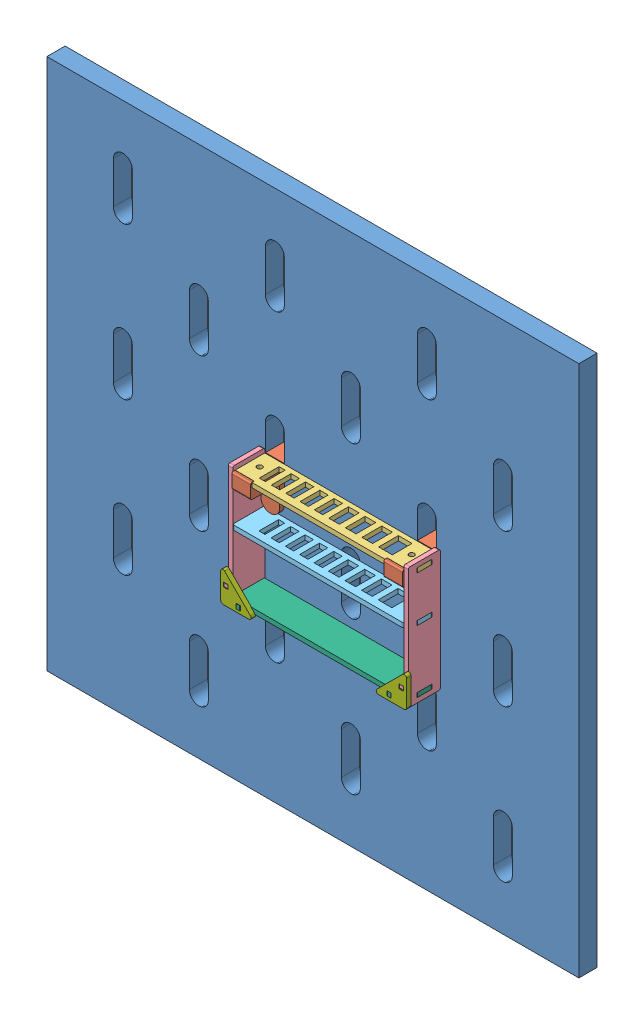
SolidWorks assembly 0 Органайзер пинцеты, configuration По умолчанию. Lengths in mm.
Overall size (350 350 46.14).
10 component instances, 7 part files, 25 mates.
Components (placement in the parent):
- 1 Стенка-1: 1 Стенка [По умолчанию] at origin size (350 350 12)
- 2 Кронштейн Пинцеты-1: 2 Кронштейн Пинцеты [По умолчанию] at (43.8 136.25 12) size (12.4 30 37.2)
- 2 Кронштейн Пинцеты-2: 2 Кронштейн Пинцеты [По умолчанию] at (143.8 136.25 12) size (12.4 30 37.2)
- 3 Полка верхняя Пинцеты-1: 3 Полка верхняя Пинцеты [По умолчанию] at (100.05 143.25 12.45) size (121.08 3 42.89)
- 4 Стенка пинцеты-1: 4 Стенка пинцеты [По умолчанию] at (40.8 109.175 22.95) size (3 80 23.85)
- 5 Полка средняя пинцеты-1: 5 Полка средняя пинцеты [По умолчанию] at (100.05 113.25 22.3) size (118.5 3 33.29)
- 4 Стенка пинцеты-2: 4 Стенка пинцеты [По умолчанию] at (156.3 109.175 22.95) size (3 80 23.85)
- 6 Полка нижняя пинцеты-1: 6 Полка нижняя пинцеты [По умолчанию] at (100.05 72.25 12.7) size (118.5 3 45.89)
- 7 уголок-1: 7 уголок [По умолчанию] at (161.3 70.25 33.7) size (22.07 22.07 3)
- 7 уголок-2: 7 уголок [По умолчанию] at (38.8 70.25 36.45) x (-1 0 0) z (0 0 -1) size (22.07 22.07 3)
Mates (geometry in assembly coordinates):
- Концентричный1: concentric aligned: cylinder of 2 Кронштейн Пинцеты-1 through (50.05 143.25 22.05) axis (0 1 0) radius 1.7; cylinder of 3 Полка верхняя Пинцеты-1 through (50.05 146.25 22.05) axis (0 1 0) radius 1.7
- Концентричный2: concentric aligned: cylinder of 2 Кронштейн Пинцеты-2 through (150.05 143.25 22.05) axis (0 1 0) radius 1.7; cylinder of 3 Полка верхняя Пинцеты-1 through (150.05 146.25 22.05) axis (0 1 0) radius 1.7
- Совпадение1: coincident anti-aligned: plane of 2 Кронштейн Пинцеты-2 through (156.2 143.25 12) normal (0 1 0); plane of 3 Полка верхняя Пинцеты-1 through (100.05 143.25 12.45) normal (0 -1 0)
- Совпадение2: coincident anti-aligned: plane of 2 Кронштейн Пинцеты-1 through (56.2 143.25 12) normal (0 1 0); plane of 3 Полка верхняя Пинцеты-1 through (100.05 143.25 12.45) normal (0 -1 0)
- Совпадение3: coincident anti-aligned: plane of 3 Полка верхняя Пинцеты-1 through (100.05 143.25 12.45) normal (0 -1 0); plane of 4 Стенка пинцеты-1 through (43.8 143.25 27.95) normal (0 1 0)
- Совпадение4: coincident anti-aligned: plane of 3 Полка верхняя Пинцеты-1 through (100.05 143.25 12.45) normal (0 -1 0); plane of 4 Стенка пинцеты-2 through (159.3 143.25 27.95) normal (0 1 0)
- Совпадение5: coincident anti-aligned: plane of 3 Полка верхняя Пинцеты-1 through (100.05 146.25 17.95) normal (0 0 -1); plane of 4 Стенка пинцеты-1 through (43.8 146.1 17.95) normal (0 0 1)
- Совпадение6: coincident aligned: plane of 3 Полка верхняя Пинцеты-1 through (40.8 146.25 12.45) normal (-1 0 0); plane of 4 Стенка пинцеты-1 through (40.8 109.175 22.95) normal (-1 0 0)
- Совпадение7: coincident anti-aligned: plane of 3 Полка верхняя Пинцеты-1 through (100.05 146.25 17.95) normal (0 0 -1); plane of 4 Стенка пинцеты-2 through (159.3 146.1 17.95) normal (0 0 1)
- Совпадение8: coincident aligned: plane of 3 Полка верхняя Пинцеты-1 through (159.3 146.25 12.45) normal (1 0 0); plane of 4 Стенка пинцеты-2 through (159.3 109.175 22.95) normal (1 0 0)
- Совпадение9: coincident anti-aligned: plane of 4 Стенка пинцеты-2 through (159.3 72.25 27.95) normal (0 1 0); plane of 6 Полка нижняя пинцеты-1 through (100.05 72.25 12.7) normal (0 -1 0)
- Совпадение10: coincident anti-aligned: plane of 4 Стенка пинцеты-2 through (159.3 75.1 17.95) normal (0 0 1); plane of 6 Полка нижняя пинцеты-1 through (100.05 75.25 17.95) normal (0 0 -1)
- Совпадение11: coincident aligned: plane of 4 Стенка пинцеты-2 through (159.3 109.175 22.95) normal (1 0 0); plane of 6 Полка нижняя пинцеты-1 through (159.3 75.25 12.7) normal (1 0 0)
- Совпадение12: coincident anti-aligned: plane of 4 Стенка пинцеты-2 through (159.3 109.175 22.95) normal (1 0 0); plane of 7 уголок-1 through (159.3 70.25 36.7) normal (-1 0 0)
- Совпадение15: coincident anti-aligned: plane of 6 Полка нижняя пинцеты-1 through (100.05 72.25 12.7) normal (0 -1 0); plane of 7 уголок-1 through (161.3 72.25 36.7) normal (0 1 0)
- Совпадение16: coincident anti-aligned: plane of 6 Полка нижняя пинцеты-1 through (100.05 75.25 33.7) normal (0 0 1); plane of 7 уголок-1 through (161.3 70.25 33.7) normal (0 0 -1)
- Совпадение17: coincident anti-aligned: plane of 4 Стенка пинцеты-1 through (40.8 109.175 22.95) normal (-1 0 0); plane of 7 уголок-2 through (40.8 70.25 33.45) normal (1 0 0)
- Совпадение18: coincident anti-aligned: plane of 6 Полка нижняя пинцеты-1 through (100.05 72.25 12.7) normal (0 -1 0); plane of 7 уголок-2 through (38.8 72.25 33.45) normal (0 1 0)
- Совпадение19: coincident anti-aligned: plane of 4 Стенка пинцеты-1 through (43.8 83.175 33.45) normal (0 0 1); plane of 7 уголок-2 through (38.8 70.25 33.45) normal (0 0 -1)
- Совпадение20: coincident anti-aligned: plane of 4 Стенка пинцеты-1 through (43.8 113.25 27.95) normal (0 1 0); plane of 5 Полка средняя пинцеты-1 through (100.05 113.25 22.3) normal (0 -1 0)
- Совпадение21: coincident anti-aligned: plane of 4 Стенка пинцеты-1 through (43.8 116.1 17.95) normal (0 0 1); plane of 5 Полка средняя пинцеты-1 through (100.05 116.25 17.95) normal (0 0 -1)
- Совпадение22: coincident aligned: plane of 4 Стенка пинцеты-1 through (40.8 109.175 22.95) normal (-1 0 0); plane of 5 Полка средняя пинцеты-1 through (40.8 116.25 22.3) normal (-1 0 0)
- Концентричный4: concentric anti-aligned: cylinder of 1 Стенка-1 through (50 136.25 12) axis (0 0 -1) radius 6.25; cylinder of 2 Кронштейн Пинцеты-1 through (50 136.25 -23.513) axis (0 0 1) radius 6.2
- Концентричный5: concentric anti-aligned: cylinder of 1 Стенка-1 through (150 136.25 12) axis (0 0 -1) radius 6.25; cylinder of 2 Кронштейн Пинцеты-2 through (150 136.25 -23.513) axis (0 0 1) radius 6.2
- Совпадение23: coincident anti-aligned: plane of 1 Стенка-1 through (0 0 12) normal (0 0 1); plane of 2 Кронштейн Пинцеты-2 through (156.2 136.25 12) normal (0 0 -1)
